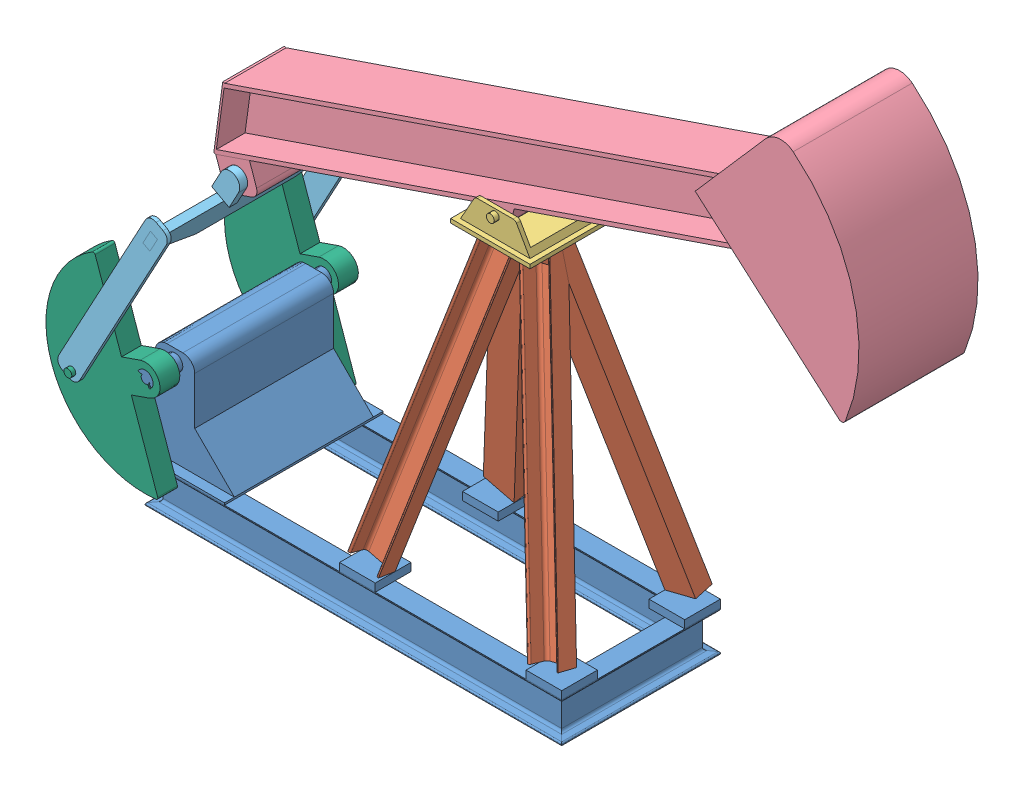
SolidWorks assembly Pump-Jack Mechanism, configuration Default. Lengths in mm.
Overall size (2089.4 1582.65 550).
8 component instances, 6 part files, 24 mates.
Components (placement in the parent):
- Base-1: Base [Default<As Machined>] x (-1 0 0) z (0 1 0) size (1050 500 355)
- Angle-1: Angle [Default<As Machined>] at (512.6199 89.3688 0) x (0 0 1) z (-0.970249 -0.24211 0) size (388 784.77 80)
- Angle-2: Angle [Default<As Machined>] at (55 70 0) x (0 0 1) z (-0.970249 0.24211 0) size (388 784.77 80)
- Connection Joint-1: Connection Joint [Default] at (245 860.7884 0) x (1 0 0) z (0 -1 0) size (200 200 75.09)
- Upper Link-1: Upper Link [Default] at (240.1501 924.9827 0) x (-0.946287 -0.323328 0) z (0 0 -1) size (1779.47 563.75 300)
- Lower Link-1: Lower Link [Default] at (-414.0492 659.1853 0) x (0.880015 -0.474946 0) z (0 0 1) size (60 545 530)
- Lower Follower-1: Lower Follower [Default] at (-475 275 -200) x (-0.329913 0.944011 0) z (0 0 -1) size (487.49 287.5 75)
- Lower Follower-2: Lower Follower [Default] at (-475 275 200) x (0.329913 -0.944011 0) z (0 0 1) size (487.49 287.5 75)
Mates (geometry in assembly coordinates):
- Coincident1: coincident aligned: plane of Base-1 through (0 0 0) normal (0 1 0)
- Coincident2: coincident aligned: plane of Base-1 through (0 0 0) normal (0 0 1)
- Coincident3: coincident anti-aligned: plane of Base-1 through (0 0 0) normal (-1 0 0)
- Width1: width anti-aligned: plane of Base-1 through (-500 35.374 -172.75) normal (0 0 1); plane of Angle-1 through (500 35.374 172.75) normal (0 0 -1); plane of Base-1 through (451.0008 75.1805 155.3779) normal (-0.050729 0.203295 0.977802); plane of Angle-1 through (281.5238 754.3547 -5.3779) normal (-0.050729 0.203295 -0.977802)
- Coincident4: coincident: plane of Base-1 through (0 70 0) normal (0 1 0); point of Angle-1
- Coincident5: coincident: plane of Base-1 through (435 70 200) normal (-1 0 0); point of Angle-1
- Width2: width aligned: plane of Base-1 through (-500 -35.374 -177.25) normal (0 0 -1); plane of Angle-2 through (500 -35.374 177.25) normal (0 0 1); plane of Base-1 through (-6.0611 86.4245 155.3779) normal (0.050729 0.203295 0.977802); plane of Angle-2 through (163.4159 765.5987 -5.3779) normal (0.050729 0.203295 -0.977802)
- Coincident6: coincident: plane of Base-1 through (0 70 0) normal (0 1 0); point of Angle-2
- Coincident7: coincident: plane of Base-1 through (55 70 -200) normal (1 0 0); point of Angle-2
- Coincident8: coincident aligned: line of Angle-1 through (245 831.4196 0) axis (0 0 -1); line of Angle-2 through (245 831.4196 0) axis (0 0 -1)
- Coincident9: coincident: line of Angle-1 through (322.6199 850.7884 27.8571) axis (0 0 -1); plane of Connection Joint-1 through (245 850.7884 0) normal (0 -1 0)
- Coincident10: coincident: line of Angle-2 through (167.3801 850.7884 27.8571) axis (0 0 -1); plane of Connection Joint-1 through (245 850.7884 0) normal (0 -1 0)
- Width3: width anti-aligned: plane of Base-1 through (-500 -35.374 -177.25) normal (0 0 -1); plane of Connection Joint-1 through (500 -35.374 177.25) normal (0 0 1); plane of Base-1 through (157.5 935.7884 87.5) normal (0 0 1); plane of Connection Joint-1 through (157.5 935.7884 -87.5) normal (0 0 -1)
- Width4: width anti-aligned: plane of Angle-1 through (510.3371 98.5171 194.0011) normal (0.970249 0.24211 0); plane of Connection Joint-1 through (-20.3371 98.5171 194.0011) normal (-0.970249 0.24211 0); plane of Angle-2 through (157.5 860.7884 -100) normal (-0.871349 0.490664 0); plane of Connection Joint-1 through (332.5 860.7884 -100) normal (0.871349 0.490664 0)
- Concentric1: concentric aligned: cylinder of Connection Joint-1 through (245 910.7884 100) axis (0 0 -1) radius 10; cylinder of Upper Link-1 through (245 910.7884 77.5) axis (0 0 -1) radius 10
- Width5: width anti-aligned: plane of Connection Joint-1 through (157.5 935.7884 -87.5) normal (0 0 -1); plane of Upper Link-1 through (157.5 935.7884 87.5) normal (0 0 1); plane of Connection Joint-1 through (946.6321 1176.9412 5) normal (0 0 1); plane of Upper Link-1 through (904.5996 1299.9585 -5) normal (0 0 -1)
- Concentric2: concentric aligned: cylinder of Upper Link-1 through (-414.0492 659.1853 150) axis (0 0 -1) radius 10; cylinder of Lower Link-1 through (-414.0492 659.1853 97.5) axis (0 0 -1) radius 10
- Width6: width anti-aligned: plane of Upper Link-1 through (240.1501 924.9827 -77.5) normal (0 0 -1); plane of Lower Link-1 through (904.5996 1299.9585 77.5) normal (0 0 1); plane of Upper Link-1 through (-414.0492 659.1853 265) normal (0 0 1); plane of Lower Link-1 through (-414.0492 659.1853 -265) normal (0 0 -1)
- Concentric3: concentric anti-aligned: cylinder of Base-1 through (-475 275 250) axis (0 0 -1) radius 20; cylinder of Lower Follower-1 through (-475 275 -250) axis (0 0 1) radius 37.5
- Coincident12: coincident aligned: plane of Base-1 through (-475 275 -250) normal (0 0 -1); plane of Lower Follower-1 through (-475 275 -250) normal (0 0 -1)
- Concentric4: concentric anti-aligned: cylinder of Lower Link-1 through (-644.922 215.6157 265) axis (0 0 -1) radius 10; cylinder of Lower Follower-1 through (-644.922 215.6157 -275) axis (0 0 1) radius 10
- Concentric5: concentric aligned: cylinder of Base-1 through (-475 275 250) axis (0 0 -1) radius 20; cylinder of Lower Follower-2 through (-475 275 250) axis (0 0 -1) radius 37.5
- Coincident13: coincident aligned: plane of Base-1 through (-475 275 250) normal (0 0 1); plane of Lower Follower-2 through (-475 275 250) normal (0 0 1)
- Concentric6: concentric aligned: cylinder of Lower Link-1 through (-644.922 215.6157 265) axis (0 0 -1) radius 10; cylinder of Lower Follower-2 through (-644.922 215.6157 275) axis (0 0 -1) radius 10
